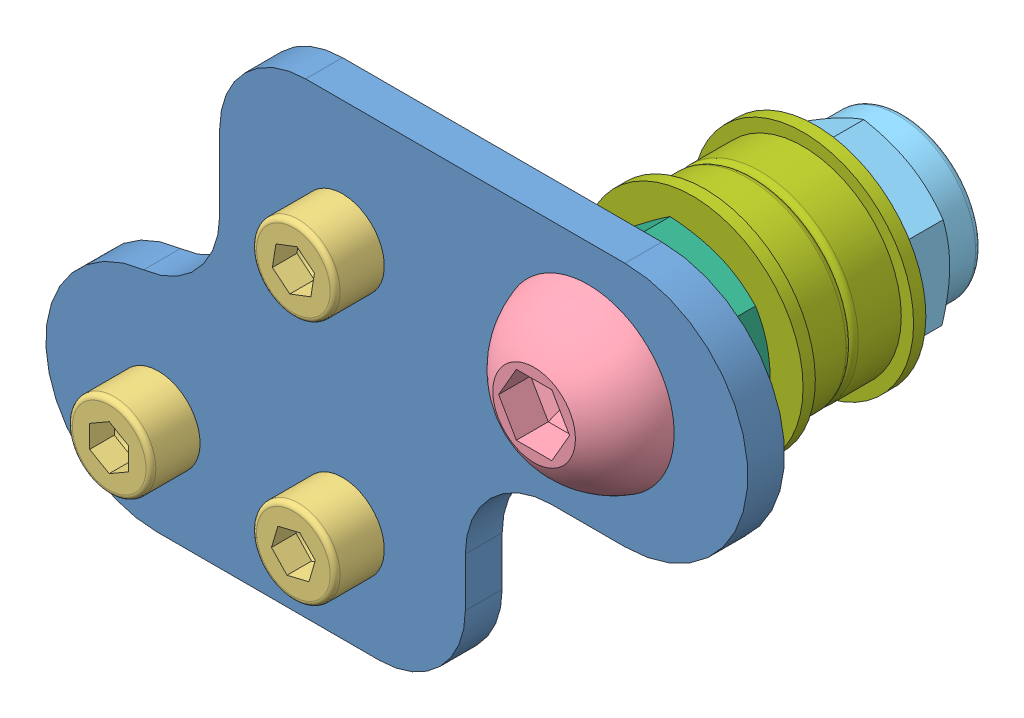
SolidWorks assembly ASM Y-Belt Tensioner, configuration Standard. Lengths in mm.
Overall size (57.16 40.7 30.9).
13 component instances, 7 part files, 20 mates.
Components (placement in the parent):
- Y Adjustment Block-1: Y Adjustment Block [Standard] x (1 0 0) z (0 1 0) size (57.16 3 38)
- M4 T-Slot Nut-1: M4 T-Slot Nut [Standard] at (-4 13 -1.1372) x (-1 0 0) z (0 0 -1) size (6 9.5 4.1)
- M4 T-Slot Nut-2: M4 T-Slot Nut [Standard] at (-19 -7 -1.1372) x (-1 0 0) z (0 0 -1) size (6 9.5 4.1)
- M4X8 Socket Head Screw-1: M4X8 Socket Head Screw [Standard] at (-19 -7 4.5001) x (0 0 -1) z (1 0 0) size (12 6.8 6.8)
- M4X8 Socket Head Screw-2: M4X8 Socket Head Screw [Standard] at (-4 13 4.5001) x (0 0 -1) z (0.987351 -0.158553 0) size (12 6.8 6.8)
- M4X8 Socket Head Screw-3: M4X8 Socket Head Screw [Standard] at (-4 -7 4.5001) x (0 0 -1) z (0.959125 -0.282984 0) size (12 6.8 6.8)
- M4 T-Slot Nut-3: M4 T-Slot Nut [Standard] at (-4 -7 -1.1372) x (-1 0 0) z (0 0 -1) size (6 9.5 4.1)
- ASM Roller Bolt-1: ASM Roller Bolt [Standard] at (16 13 8.9001) x (0 0 -1) z (1 0 0) size (30.9 25.4 25.4)
  - M8X25 Pan Head Screw-1: M8X25 Pan Head Screw [Standard] at origin size (30.62 14.79 14.79)
  - M8 Self-locking nut-1: M8 Self-locking nut [Standard] at (27.7325 0 0) x (0 0.488663 0.872473) z (1 0 0) size (15.01 13 7.18)
  - M8 nut-1: M8 nut [Standard] at (7.4 0 0) x (0 0.613039 0.790053) z (-1 0 0) size (15.01 13 5.5)
  - F688 pillow-1: F688 pillow [Standard] at (22.9 0 0) x (0 0.424513 0.905422) z (0 -0.905422 0.424513) size (18 5 18)
  - F688 pillow-2: F688 pillow [Standard] at (12.9 0 0) x (0 0.751639 -0.659574) z (0 -0.659574 -0.751639) size (18 5 18)
Mates (geometry in assembly coordinates):
- Konzentrisch1: concentric aligned: cylinder of Y Adjustment Block-1 through (-19 -7 6.5001) axis (0 0 1) radius 2.25; cylinder of M4 T-Slot Nut-2 through (-19 -7 -4.0662) axis (0 0 1) radius 2
- Konzentrisch3: concentric aligned: cylinder of Y Adjustment Block-1 through (-4 13 1.5001) axis (0 0 1) radius 2.25; cylinder of M4 T-Slot Nut-1 through (-4 13 -4.0662) axis (0 0 1) radius 2
- Konzentrisch4: concentric aligned: cylinder of Y Adjustment Block-1 through (-19 -7 6.5001) axis (0 0 1) radius 2.25; cylinder of M4X8 Socket Head Screw-1 through (-19 -7 5.4417) axis (0 0 1) radius 2
- Deckungsgleich11: coincident anti-aligned: plane of Y Adjustment Block-1 through (6.5 13 4.5001) normal (0 0 1); plane of M4X8 Socket Head Screw-1 through (-19 -3.6 4.5001) normal (0 0 -1)
- Deckungsgleich12: coincident anti-aligned: plane of Y Adjustment Block-1 through (6.5 13 4.5001) normal (0 0 1); plane of M4X8 Socket Head Screw-2 through (-3.4609 16.357 4.5001) normal (0 0 -1)
- Konzentrisch5: concentric aligned: cylinder of Y Adjustment Block-1 through (-4 13 1.5001) axis (0 0 1) radius 2.25; cylinder of M4X8 Socket Head Screw-2 through (-4 13 5.4417) axis (0 0 1) radius 2
- Deckungsgleich13: coincident anti-aligned: plane of Y Adjustment Block-1 through (6.5 13 4.5001) normal (0 0 1); plane of M4X8 Socket Head Screw-3 through (-3.0379 -3.739 4.5001) normal (0 0 -1)
- Konzentrisch6: concentric aligned: cylinder of Y Adjustment Block-1 through (-4 -7 6.5001) axis (0 0 1) radius 2.25; cylinder of M4X8 Socket Head Screw-3 through (-4 -7 5.4417) axis (0 0 1) radius 2
- Konzentrisch7: concentric aligned: cylinder of Y Adjustment Block-1 through (16 13 6.5001) axis (0 0 1) radius 4.05; cylinder of ASM Roller Bolt-1/M8X25 Pan Head Screw-1 through (16 13 -5.4999) axis (0 0 1) radius 4
- Deckungsgleich14: coincident anti-aligned: plane of Y Adjustment Block-1 through (6.5 13 4.5001) normal (0 0 1); plane of ASM Roller Bolt-1/M8X25 Pan Head Screw-1 through (16 13 4.5001) normal (0 0 -1)
- Konzentrisch31: concentric aligned: cylinder of Y Adjustment Block-1 through (-4 -7 6.5001) axis (0 0 1) radius 2.25; cylinder of M4 T-Slot Nut-3 through (-4 -7 -4.0662) axis (0 0 1) radius 2
- Parallel1: parallel aligned: plane of Y Adjustment Block-1 through (-14 23 1.5001) normal (-1 0 0); plane of M4 T-Slot Nut-1 through (-7 13 -1.1372) normal (-1 0 0)
- Parallel2: parallel aligned: plane of M4 T-Slot Nut-1 through (-7 13 -1.1372) normal (-1 0 0); plane of M4 T-Slot Nut-3 through (-7 -7 -1.1372) normal (-1 0 0)
- Parallel3: parallel aligned: plane of M4 T-Slot Nut-2 through (-22 -7 -1.1372) normal (-1 0 0); plane of M4 T-Slot Nut-3 through (-7 -7 -1.1372) normal (-1 0 0)
- Deckungsgleich15: coincident aligned: plane of M4 T-Slot Nut-2 through (-22 -11.75 -0.2999) normal (0 0 1); plane of M4 T-Slot Nut-3 through (-7 -11.75 -0.2999) normal (0 0 1)
- Deckungsgleich16: coincident aligned: plane of M4 T-Slot Nut-1 through (-7 8.25 -0.2999) normal (0 0 1); plane of M4 T-Slot Nut-3 through (-7 -11.75 -0.2999) normal (0 0 1)
- Abstand1: distance = 1.8 mm anti-aligned: plane of M4 T-Slot Nut-1 through (-7 8.25 -0.2999) normal (0 0 1); plane of Y Adjustment Block-1 through (6.5 13 1.5001) normal (0 0 -1)
- Deckungsgleich17: coincident aligned: plane of Y Adjustment Block-1 through (0 0 0) normal (0 1 0); plane of assembly through (0 0 0) normal (0 1 0)
- Deckungsgleich18: coincident aligned: line of Y Adjustment Block-1 through (-1.65 0 0) axis (0 1 0); plane of assembly through (0 0 0) normal (1 0 0)
- Deckungsgleich19: coincident anti-aligned: plane of Y Adjustment Block-1 through (0 0 0) normal (0 0 -1); plane of assembly through (0 0 0) normal (0 0 1)
